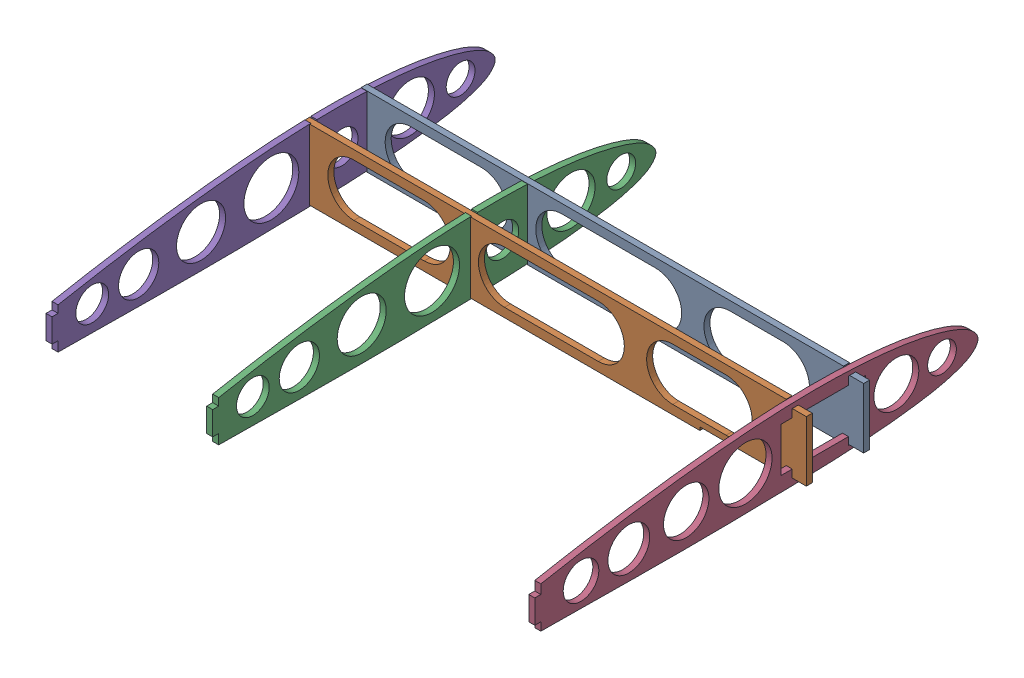
SolidWorks assembly innerWing_structure_R, configuration Default. Lengths in mm.
Overall size (250.29 36.78 220.85).
5 component instances, 3 part files, 12 mates.
Components (placement in the parent):
- stringer_inner-1: stringer_inner [Default] at (-9.4796 85.0992 -3) x (1 0 0) z (0 -1 0) size (250.28 3 35)
- stringer_inner-2: stringer_inner [Default] at (-9.4796 85.0992 25.5588) x (1 0 0) z (0 -1 0) size (250.28 3 35)
- wingStructure_innerRib-1: wingStructure_innerRib [Default] at (424.0204 77.7584 -64.3108) x (0 0 1) z (-1 0 0) size (220.72 36.52 3.02)
- wingStructure_foldingmech_inner_Rib-1: wingStructure_foldingmech_inner_Rib [Default] at (584.3004 77.4943 -64.4412) x (0 0 1) z (-1 0 0) size (220.72 36.52 3.02)
- wingStructure_innerRib-3: wingStructure_innerRib [Default] at (344.0204 77.7584 -64.3108) x (0 0 1) z (-1 0 0) size (220.72 36.52 3.02)
Mates (geometry in assembly coordinates):
- Coincident1: coincident aligned: plane of stringer_inner-1 through (-9.4796 85.0992 0) normal (0 0 1)
- Coincident13: coincident anti-aligned: plane of stringer_inner-1 through (-9.4796 85.0992 -3) normal (0 0 -1); plane of wingStructure_innerRib-1 through (83.4434 84.5992 -3) normal (0 0 1)
- Coincident14: coincident anti-aligned: plane of stringer_inner-1 through (70.5204 67.5992 -3) normal (1 0 0); plane of wingStructure_innerRib-1 through (70.5204 87.4487 -62.3801) normal (-1 0 0)
- Coincident15: coincident anti-aligned: plane of stringer_inner-1 through (70.5204 84.5992 -3) normal (0 -1 0); plane of wingStructure_innerRib-1 through (83.4434 84.5992 -3) normal (0 1 0)
- Coincident33: coincident anti-aligned: plane of stringer_inner-2 through (230.8004 102.5992 15.251) normal (1 0 0); plane of wingStructure_foldingmech_inner_Rib-1 through (230.8004 87.1846 -62.5106) normal (-1 0 0)
- Coincident34: coincident anti-aligned: plane of stringer_inner-2 through (240.8004 70.0992 15.251) normal (0 -1 0); plane of wingStructure_foldingmech_inner_Rib-1 through (285.4143 70.0992 25.5588) normal (0 1 0)
- Coincident35: coincident anti-aligned: plane of stringer_inner-2 through (-9.4796 85.0992 25.5588) normal (0 0 -1); plane of wingStructure_foldingmech_inner_Rib-1 through (285.4143 73.9892 25.5588) normal (0 0 1)
- Coincident36: coincident anti-aligned: cylinder of wingStructure_innerRib-1 through (83.4434 84.5992 12.5) axis (-1 0 0) radius 8; circle of wingStructure_innerRib-3
- Coincident37: coincident anti-aligned: plane of stringer_inner-1 through (240.8004 70.0992 -13.3078) normal (0 -1 0); plane of wingStructure_foldingmech_inner_Rib-1 through (285.4143 70.0992 -2.4412) normal (0 1 0)
- Coincident38: coincident anti-aligned: plane of stringer_inner-1 through (230.8004 102.5992 -13.3078) normal (1 0 0); plane of wingStructure_foldingmech_inner_Rib-1 through (230.8004 87.1846 -62.5106) normal (-1 0 0)
- Parallel1: parallel anti-aligned: plane of stringer_inner-1 through (-9.4796 85.0992 -10) normal (0 -1 0); plane of wingStructure_innerRib-3 through (3.4434 84.5992 -3) normal (0 1 0)
- Coincident40: coincident anti-aligned: plane of stringer_inner-1 through (-6.4796 85.0992 -10) normal (-1 0 0); plane of wingStructure_innerRib-3 through (-6.4796 87.4487 -62.3801) normal (1 0 0)
